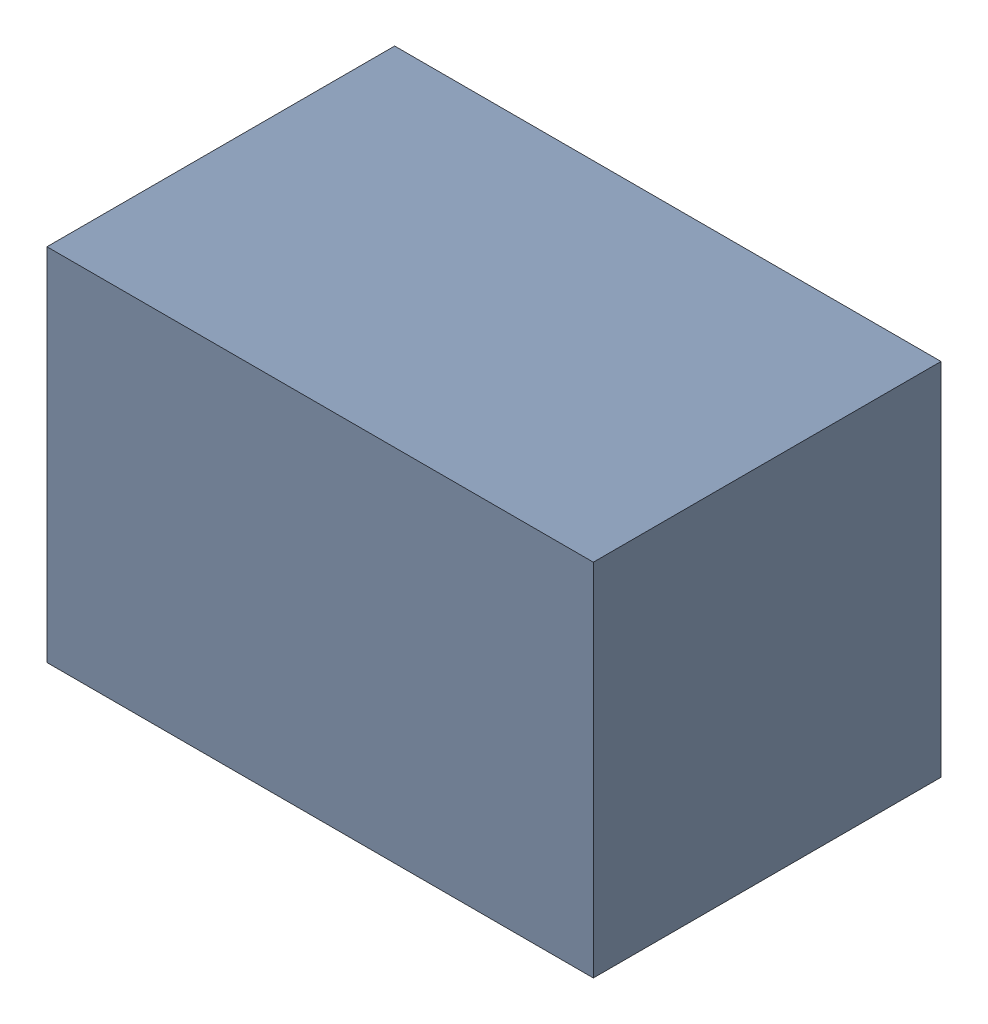
SolidWorks assembly C20, configuration Default. Lengths in mm.
Overall size (2.2 1.45 1.4).
2 component instances, 1 part files, 0 mates.
Components (placement in the parent):
- 1017092848-1: 1017092848 [Default] at (110.49 144.78 0) size (2.2 1.45 1.4)
  - Extruded_3-1: Extruded_3 [Default] at origin size (2.2 1.45 1.4)
